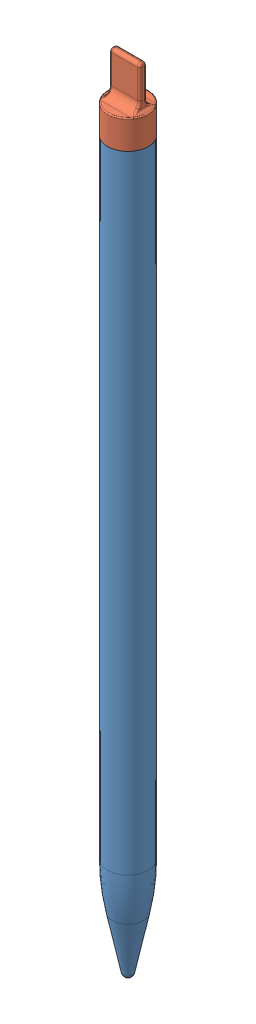
SolidWorks assembly Pencil_Assembly, configuration Default. Lengths in mm.
Overall size (8.9 175.14 8.9).
2 component instances, 2 part files, 3 mates.
Components (placement in the parent):
- Pencil_Body-1: Pencil_Body [Default] at (-27.7441 -68.4289 6.3667) size (8.85 159.79 8.85)
- Male_Lightning-2: Male_Lightning [Default] at (-27.7441 92.0711 6.3667) size (8.9 15.35 8.9)
Mates (geometry in assembly coordinates):
- Coincident3: coincident: plane of Pencil_Body-1 through (-27.7441 92.0711 6.3667) normal (0 1 0); plane of Male_Lightning-2 through (-27.7441 92.0711 6.3667) normal (0 -1 0)
- Concentric2: concentric: cylinder of Pencil_Body-1 through (-27.7441 92.0711 6.3667) axis (0 1 0) radius 4.425; cylinder of Male_Lightning-2 through (-27.7441 98.3711 6.3667) axis (0 -1 0) radius 4.45
- Parallel3: parallel: plane of Male_Lightning-2 through (-24.4191 107.4211 5.6167) normal (1 0 0); plane of assembly
